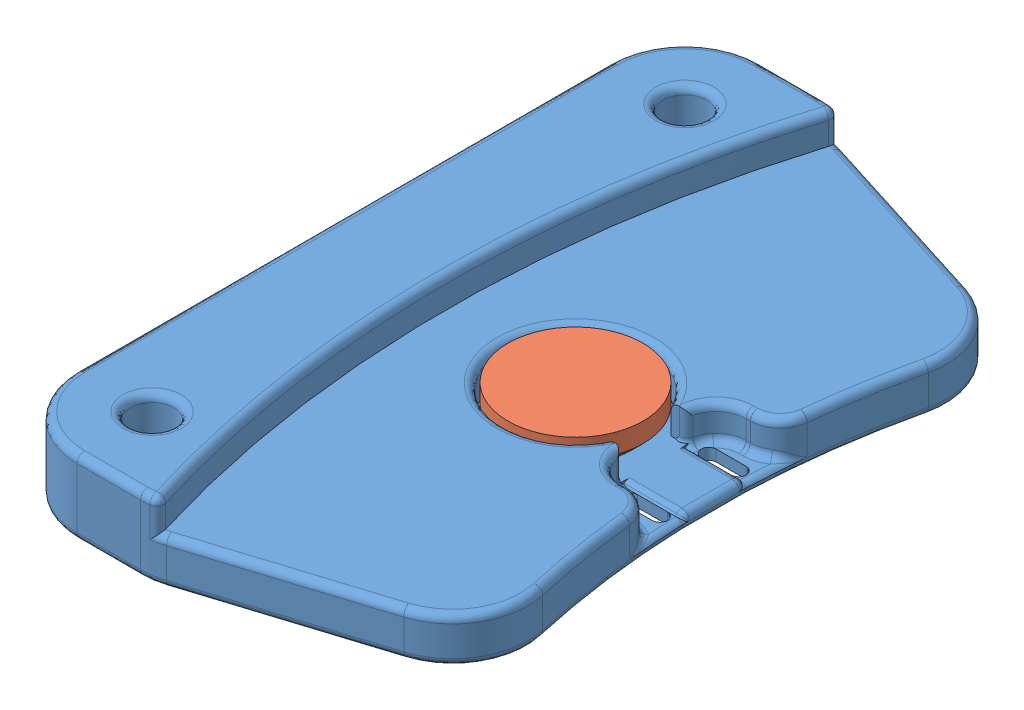
SolidWorks assembly assembled_bedrest-fsr, configuration Default. Lengths in mm.
Overall size (52.5 10 91.02).
2 component instances, 2 part files, 2 mates.
Components (placement in the parent):
- bedrest-fsr-1: bedrest-fsr [Default] at origin size (52.5 10 91.02)
- bedrest-fsr-foot-2: bedrest-fsr-foot [Default] at (-133.4178 4.1 0) x (1 0 0) z (0 1 0) size (18 18 4.1)
Mates (geometry in assembly coordinates):
- Coincident4: coincident anti-aligned: plane of bedrest-fsr-1 through (0 0 0) normal (0 1 0); plane of bedrest-fsr-foot-2 through (-140.9178 0 0) normal (0 -1 0)
- Concentric1: concentric anti-aligned: line of bedrest-fsr-1 through (-133.4178 0 0) axis (0 1 0); circle of bedrest-fsr-foot-2
